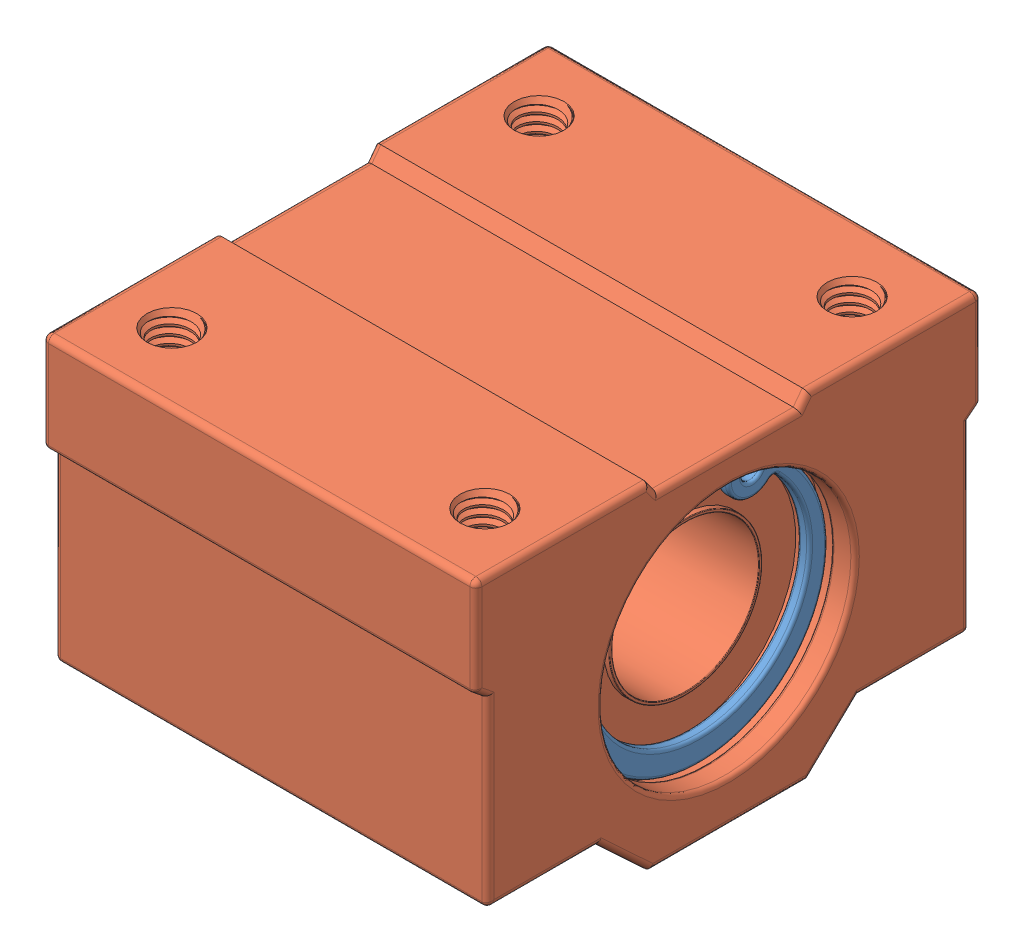
SolidWorks assembly Montagem1, configuration Valor predeterminado. Lengths in mm.
Overall size (36 28.21 42).
3 component instances, 2 part files, 0 mates.
Components (placement in the parent):
- CLAMP-1: CLAMP [Valor predeterminado] at (13.886 -11.8235 21.4636) x (0 0 1) z (-1 0 0) size (21.2 20.68 1.18)
- pillow 12mm M4-1: pillow 12mm M4 [Valor predeterminado] at (10.5245 -11.8137 21.45) size (36 28.21 42)
- CLAMP-2: CLAMP [Valor predeterminado] at (44.1964 -11.8301 21.4981) x (0 0 1) z (-1 0 0) size (21.2 20.68 1.18)
